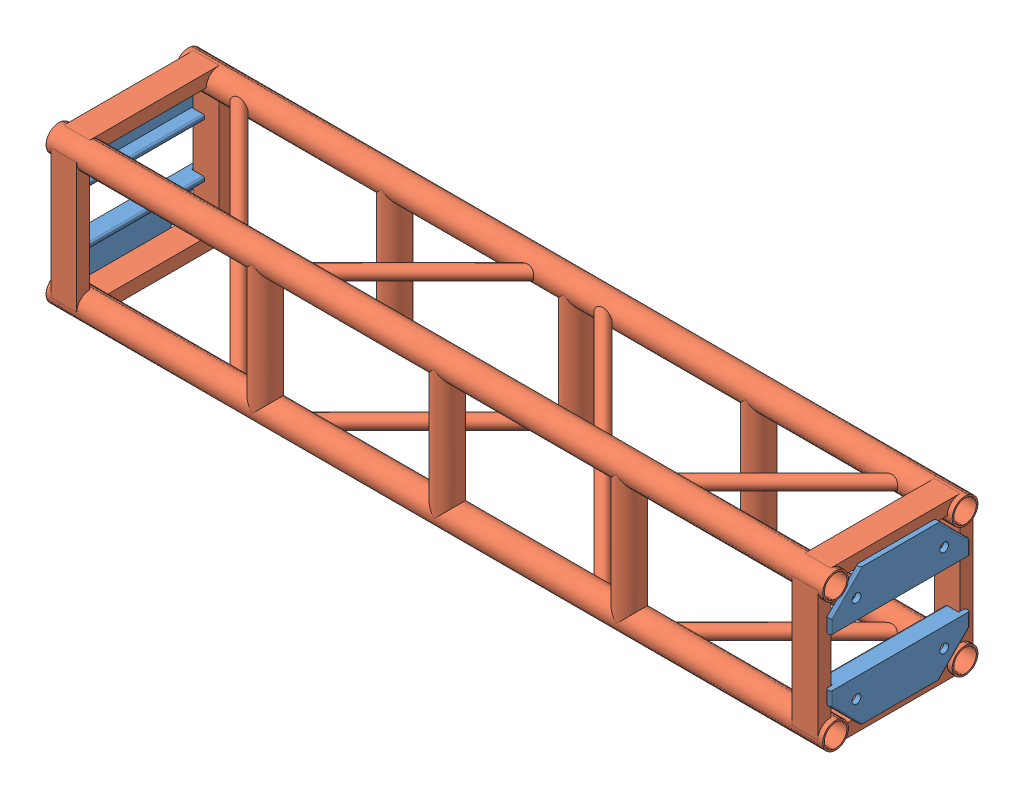
SolidWorks assembly FE-01003, configuration Default. Lengths in mm.
Overall size (1524 304.8 304.8).
5 component instances, 2 part files, 0 mates.
Components (placement in the parent):
- Connection Plate _ TS Standard-3: Connection Plate _ TS Standard [Default] at (-744.5375 -90.7415 0) x (0 0 -1) z (1 0 0) size (273.05 85.72 34.92)
- Connection Plate _ TS Standard-2: Connection Plate _ TS Standard [Default] at (-744.5375 90.7415 0) x (0 0 1) z (1 0 0) size (273.05 85.72 34.92)
- Connection Plate _ TS Standard-4: Connection Plate _ TS Standard [Default] at (744.5375 -90.7415 0) x (0 0 1) z (-1 0 0) size (273.05 85.72 34.92)
- Connection Plate _ TS Standard-5: Connection Plate _ TS Standard [Default] at (744.5375 90.7415 0) x (0 0 -1) z (-1 0 0) size (273.05 85.72 34.92)
- FE-01003-01-1: FE-01003-01 [Default] at origin size (1524 304.8 304.8)
